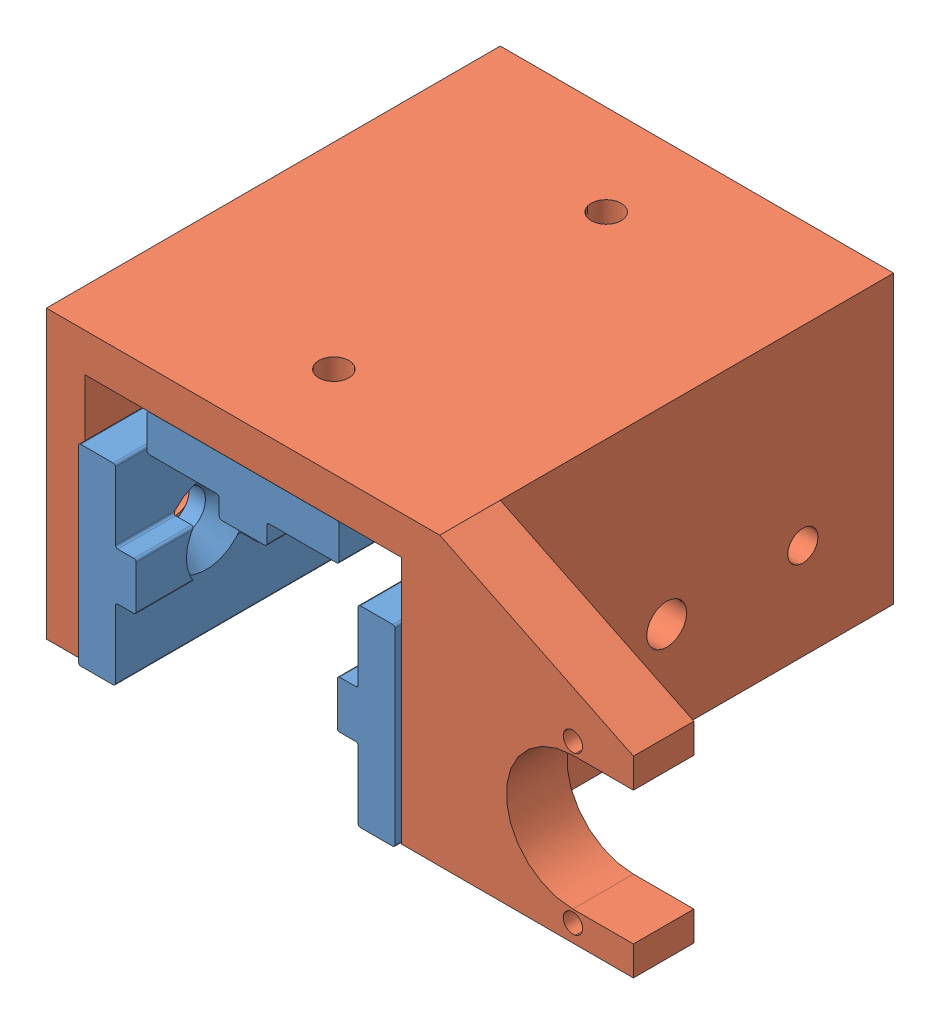
SolidWorks assembly Frame Carriage Assembly LH, configuration Default. Lengths in mm.
Overall size (97 47.37 76.04).
4 component instances, 2 part files, 13 mates.
Components (placement in the parent):
- Frame Carriage Bearing-1: Frame Carriage Bearing [Default] at (0.67 46.0259 29.8884) size (9.53 31.75 75)
- Frame Carriage Bearing-2: Frame Carriage Bearing [Default] at (40.778 46.0259 29.8884) x (-1 0 0) z (0 0 1) size (9.53 31.75 75)
- Frame Carriage Bearing-3: Frame Carriage Bearing [Default] at (20.724 65.0476 78.4503) x (0 -1 0) z (0 0 -1) size (9.53 31.75 75)
- Frame Carriage Body LH-1: Frame Carriage Body LH [Default] at (-11.776 30.1509 16.1503) size (97 47.37 75)
Mates (geometry in assembly coordinates):
- Coincident1: coincident: plane of ? through (-13.8584 24.4943 92.1884) normal (0 0 1); plane of Frame Carriage Bearing-1 through (-7.1274 55.8623 92.1884) normal (0 0 1)
- Coincident2: coincident: plane of ? through (-13.8584 24.4943 92.1884) normal (0 0 1); plane of Frame Carriage Bearing-3 through (34.1356 65.1333 92.1884) normal (0 0 1)
- Coincident3: coincident: plane of ? through (-13.8584 24.4943 92.1884) normal (0 0 1); plane of Frame Carriage Bearing-2 through (44.4106 24.8743 92.1884) normal (0 0 1)
- Coincident4: coincident: plane of ? through (-7.5084 24.4943 92.1884) normal (1 0 0); plane of Frame Carriage Bearing-1 through (-7.5084 55.8623 42.5884) normal (-1 0 0)
- Coincident5: coincident: plane of ? through (44.7916 65.5143 92.1884) normal (-1 0 0); plane of Frame Carriage Bearing-2 through (44.7916 24.8743 42.5884) normal (1 0 0)
- Coincident6: coincident: plane of ? through (-7.5084 65.5143 92.1884) normal (0 -1 0); plane of Frame Carriage Bearing-3 through (3.1476 65.5143 66.7884) normal (0 1 0)
- Distance2: distance = 19.05 mm: moEndPointRef_w of Frame Carriage Bearing-1; line of Frame Carriage Bearing-3 through (16.406 65.0476 91.1503) axis (-1 0 0)
- Coincident10: coincident: plane of Frame Carriage Bearing-1 through (-5.045 30.1509 42.5884) normal (0 -1 0); plane of Frame Carriage Bearing-2 through (41.159 30.1509 42.5884) normal (0 -1 0)
- Symmetric1: symmetric: plane of Frame Carriage Bearing-3 through (4.849 65.4286 65.7503) normal (-1 0 0); plane of Frame Carriage Bearing-3 through (36.599 70.7626 65.7503) normal (1 0 0); plane of assembly
- Coincident11: coincident: plane of Frame Carriage Bearing-3 through (36.218 70.7626 91.1503) normal (0 0 1); plane of Frame Carriage Body LH-1 through (-11.776 30.1509 91.1503) normal (0 0 1)
- Coincident12: coincident: plane of Frame Carriage Bearing-2 through (46.874 30.5319 42.5884) normal (1 0 0); plane of Frame Carriage Body LH-1 through (46.874 63.6709 91.1503) normal (-1 0 0)
- Coincident13: coincident: plane of Frame Carriage Bearing-2 through (41.159 30.1509 42.5884) normal (0 -1 0); plane of Frame Carriage Body LH-1 through (53.224 30.1509 91.1503) normal (0 -1 0)
- Coincident14: coincident: plane of Frame Carriage Bearing-1 through (-5.426 61.5199 42.5884) normal (-1 0 0); plane of Frame Carriage Body LH-1 through (-5.426 30.1509 91.1503) normal (1 0 0)
